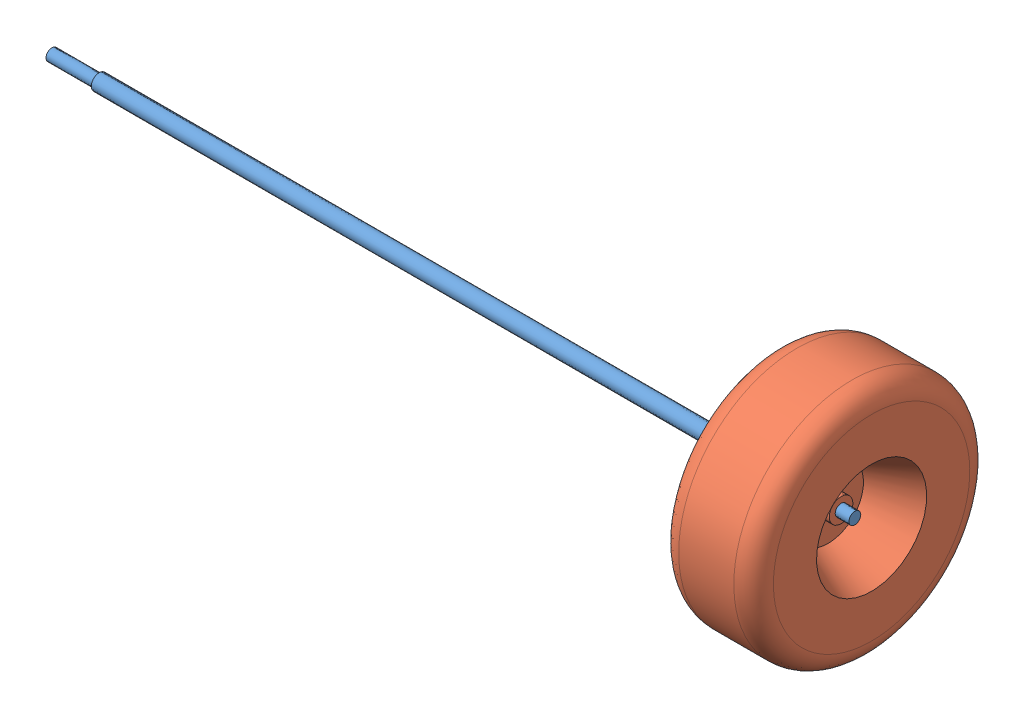
SolidWorks assembly ASM Rear Axle, configuration Default. Lengths in mm.
Overall size (1322.39 458.56 458.56).
3 component instances, 2 part files, 7 mates.
Components (placement in the parent):
- ACSV Soapbox Rear Axle-1: ACSV Soapbox Rear Axle [Default] at origin size (1295.4 25.4 25.4)
- ACSV Soapbox Wheel 2-1: ACSV Soapbox Wheel 2 [Default] at (-598.4875 0 0) (suppressed, hidden)
- ACSV Soapbox Wheel 2-4: ACSV Soapbox Wheel 2 [Default] at (598.4875 0 0) x (-1 0 0) z (0 0.973077 0.230481)
Mates (geometry in assembly coordinates):
- Coincident1: coincident aligned: plane of ACSV Soapbox Rear Axle-1 through (0 0 0) normal (1 0 0)
- Coincident2: coincident aligned: plane of ACSV Soapbox Rear Axle-1 through (0 0 0) normal (0 1 0)
- Coincident3: coincident aligned: plane of ACSV Soapbox Rear Axle-1 through (0 0 0) normal (0 0 1)
- Coincident4: coincident anti-aligned: plane of ACSV Soapbox Rear Axle-1 through (-571.5 0 -9.525) normal (-1 0 0); plane of ACSV Soapbox Wheel 2-1 through (-571.5 9.525 0) normal (1 0 0)
- Concentric1: concentric aligned: cylinder of ACSV Soapbox Rear Axle-1 through (-647.7 0 0) axis (-1 0 0) radius 9.525; cylinder of ACSV Soapbox Wheel 2-1 through (-674.6875 0 0) axis (-1 0 0) radius 9.525
- Concentric4: concentric anti-aligned: cylinder of ACSV Soapbox Rear Axle-1 through (-647.7 0 0) axis (-1 0 0) radius 9.525; cylinder of ACSV Soapbox Wheel 2-4 through (674.6875 0 0) axis (1 0 0) radius 9.525
- Coincident7: coincident anti-aligned: plane of ACSV Soapbox Rear Axle-1 through (571.5 0 -9.525) normal (1 0 0); plane of ACSV Soapbox Wheel 2-4 through (571.5 -2.1953 9.2686) normal (-1 0 0)
